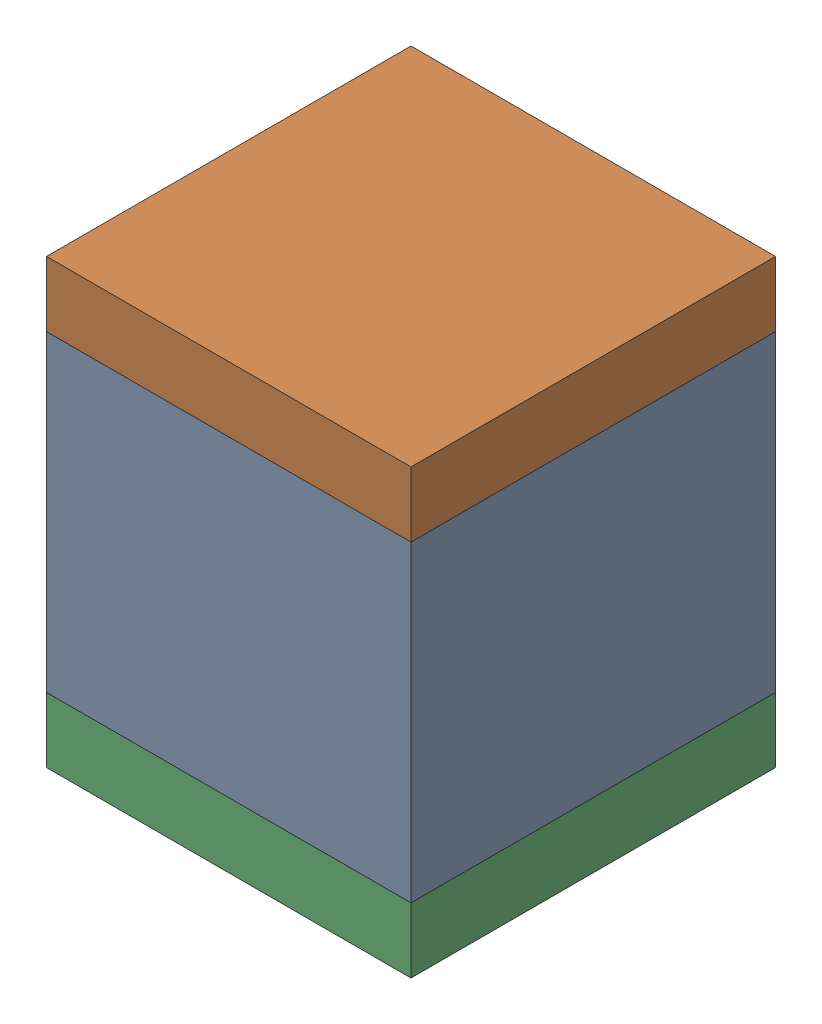
SolidWorks assembly C414PCB, configuration Default. Lengths in mm.
Overall size (2.8 3.4 2.8).
6 component instances, 2 part files, 0 mates.
Components (placement in the parent):
- 846484376-1: 846484376 [Default] at (91.19 80.2 0) size (2.8 2.4 2.8)
  - Extruded_31-1: Extruded_31 [Default] at origin size (2.8 2.4 2.8)
- 846484512-1: 846484512 [Default] at (91.19 81.65 0) size (2.8 0.5 2.8)
  - Extruded_32-1: Extruded_32 [Default] at origin size (2.8 0.5 2.8)
- 846484512-2: 846484512 [Default] at (91.19 78.75 0) size (2.8 0.5 2.8)
  - Extruded_32-1: Extruded_32 [Default] at origin size (2.8 0.5 2.8)
